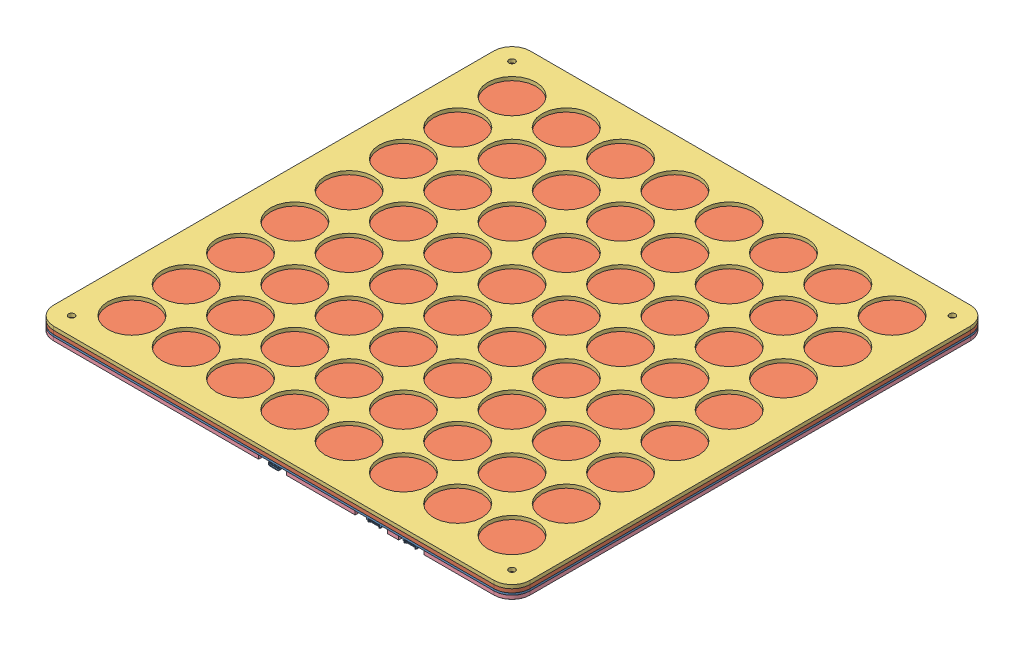
SolidWorks assembly Assembly, configuration Default. Lengths in mm.
Overall size (395 11 395).
4 component instances, 4 part files, 9 mates.
Components (placement in the parent):
- PCB-1: PCB [Default] x (-1 0 0) z (0 -1 0) size (395 395 5)
- Middle-1: Middle [Default] at (-197.5 1.6194 -197.5) size (395 3 395)
- Top-1: Top [Default] at (-197.5 4.6194 -197.5) size (395 3 395)
- Bottom-2: Bottom [Default] at (-197.5 0 -197.5) x (-1 0 0) z (0 0 1) size (395 3 395)
Mates (geometry in assembly coordinates):
- Concentric1: concentric: cylinder of PCB-1 through (-15 1.6194 -15) axis (0 -1 0) radius 2.55; cylinder of Middle-1 through (-15 4.6194 -15) axis (0 -1 0) radius 2.55
- Concentric2: concentric: cylinder of PCB-1 through (-380 1.6194 -15) axis (0 -1 0) radius 2.55; cylinder of Middle-1 through (-380 4.6194 -15) axis (0 -1 0) radius 2.55
- Coincident1: coincident: plane of PCB-1 through (-197.5 1.6194 -197.5) normal (0 1 0); plane of Middle-1 through (-197.5 1.6194 -197.5) normal (0 -1 0)
- Concentric3: concentric: cylinder of Middle-1 through (-15 4.6194 -15) axis (0 -1 0) radius 2.55; cylinder of Top-1 through (-15 7.6194 -15) axis (0 -1 0) radius 2.55
- Concentric4: concentric: cylinder of Middle-1 through (-380 4.6194 -15) axis (0 -1 0) radius 2.55; cylinder of Top-1 through (-380 7.6194 -15) axis (0 -1 0) radius 2.55
- Coincident2: coincident: plane of Middle-1 through (-197.5 4.6194 -197.5) normal (0 1 0); plane of Top-1 through (-197.5 4.6194 -197.5) normal (0 -1 0)
- Coincident4: coincident: plane of PCB-1 through (-197.5 0 -197.5) normal (0 -1 0); plane of Bottom-2 through (-197.5 0 -197.5) normal (0 1 0)
- Concentric7: concentric: cylinder of PCB-1 through (-380 1.6194 -380) axis (0 -1 0) radius 2.55; cylinder of Bottom-2 through (-380 -3 -380) axis (0 1 0) radius 2.55
- Concentric8: concentric: cylinder of PCB-1 through (-15 1.6194 -15) axis (0 -1 0) radius 2.55; cylinder of Bottom-2 through (-15 -3 -15) axis (0 1 0) radius 2.55
